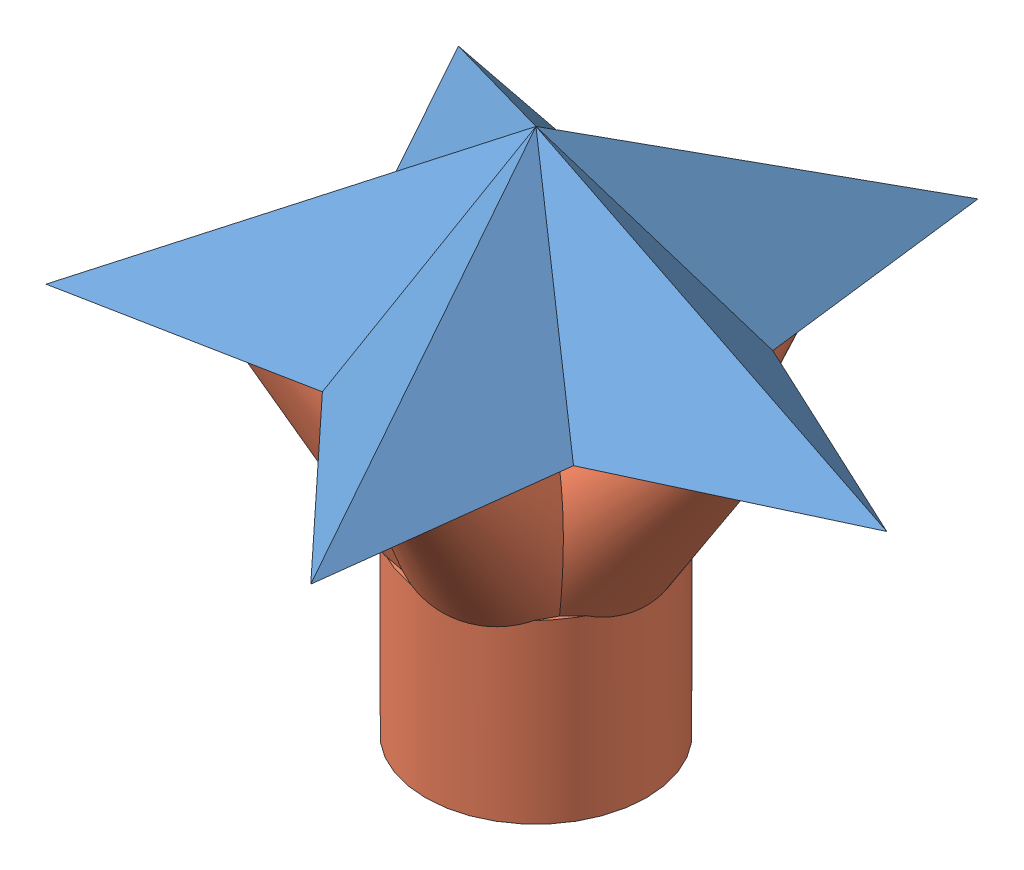
SolidWorks assembly casting_assemblyb, configuration Default. Lengths in mm.
Overall size (45.96 38.11 48.32).
2 component instances, 2 part files, 3 mates.
Components (placement in the parent):
- star_5pt25d_08032013-1: star_5pt25d_08032013 [Default] at (-32.0329 17.7307 -0.7366) size (45.96 12.71 48.32)
- star_casting_sprues_round-1: star_casting_sprues_round [Default] at (-27.7903 19.852 -0.7366) x (0 0 -1) z (-1 0 0) size (32.33 27.52 31.02)
Mates (geometry in assembly coordinates):
- Coincident1: coincident anti-aligned: plane of star_5pt25d_08032013-1 through (-32.0329 17.7307 -0.7366) normal (0 -1 0); plane of star_casting_sprues_round-1 through (-35.4653 17.7307 1.7572) normal (0 1 0)
- Coincident2: coincident aligned: line of star_5pt25d_08032013-1 through (-32.0329 44.6772 -0.7366) axis (0 -1 0); line of star_casting_sprues_round-1 through (-32.0329 23.1027 -0.7366) axis (0 -1 0)
- Parallel2: parallel aligned: line of star_casting_sprues_round-1 through (-27.7903 19.852 -0.7366) axis (1 0 0); line of star_5pt25d_08032013-1 through (-32.0329 17.7307 -0.7366) axis (1 0 0)
